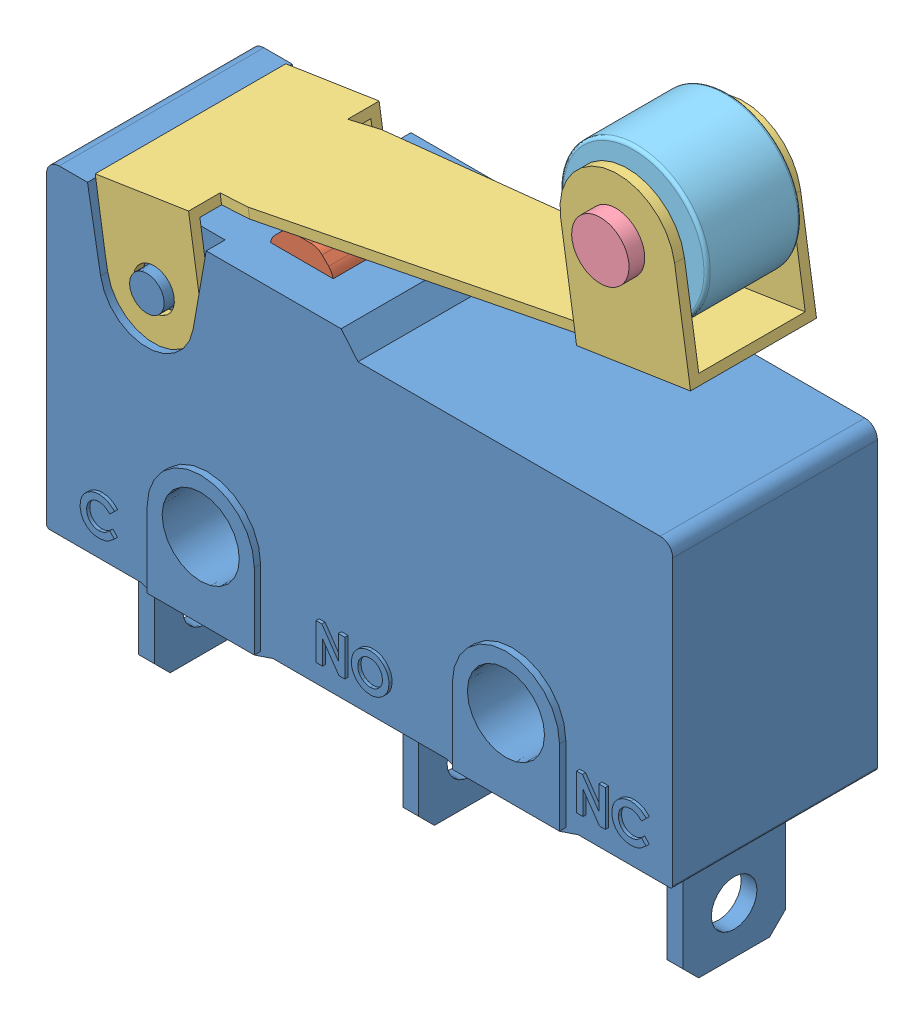
SolidWorks assembly Limit Switch, configuration Default. Lengths in mm.
Overall size (19.88 22.22 6.9).
5 component instances, 5 part files, 9 mates.
Components (placement in the parent):
- Body-1: Body [Default] at (-3.0926 15.7185 13.5391) size (19.88 14.3 6.9)
- Switch_Button-1: Switch_Button [Default] at (3.7604 12.3412 16.7891) size (2 4 4)
- Link-1: Link [Default] at (-1.7251 15.5431 16.7891) x (0.988221 0.153035 0) z (0 0 1) size (18.04 8.82 6.05)
- Wheel shaft-1: Wheel shaft [Default] at (13.789 21.2849 14.2391) x (-0.16928 0.985568 0) z (0 0 1) size (1.82 1.82 5.1)
- Wheel-1: Wheel [Default] at (13.789 21.2849 15.2941) x (0.999957 0.009288 0) z (0 0 1) size (4.67 4.67 2.99)
Mates (geometry in assembly coordinates):
- Coincident1: coincident anti-aligned: plane of Body-1 through (2.7604 13.7185 18.7891) normal (0 0 -1); plane of Switch_Button-1 through (2.7604 16.3412 18.7891) normal (0 0 1)
- Coincident2: coincident anti-aligned: plane of Body-1 through (4.7604 13.7185 14.7891) normal (-1 0 0); plane of Switch_Button-1 through (4.7604 16.3412 14.7891) normal (1 0 0)
- Concentric1: concentric aligned: cylinder of Body-1 through (0.0924 13.6084 19.4391) axis (0 0 1) radius 0.55; cylinder of Link-1 through (0.0924 13.6084 8.8141) axis (0 0 1) radius 0.65
- Tangent1: tangent anti-aligned: cylinder of Switch_Button-1 through (3.4675 15.8412 16.7891) axis (0 0 1) radius 0.5; plane of Link-1 through (-1.7251 15.5431 16.7891) normal (0.153035 -0.988221 0)
- Symmetric1: symmetric aligned: plane of Body-1 through (16.3874 14.6785 13.5391) normal (0 0 -1); plane of Link-1 through (16.3874 14.6785 20.0391) normal (0 0 1); plane of Body-1 through (-1.7251 15.5431 16.7891) normal (0 0 1)
- Concentric2: concentric aligned: cylinder of Link-1 through (13.789 21.2849 19.6091) axis (0 0 -1) radius 0.75; cylinder of Wheel shaft-1 through (13.789 21.2849 19.3391) axis (0 0 -1) radius 0.5
- Symmetric2: symmetric aligned: plane of Link-1 through (-1.7251 15.5431 16.7891) normal (0 0 1); plane of Wheel shaft-1 through (13.789 21.2849 19.3391) normal (0 0 1); plane of Wheel shaft-1 through (13.789 21.2849 14.2391) normal (0 0 -1)
- Concentric3: concentric aligned: cylinder of Wheel shaft-1 through (13.789 21.2849 19.3391) axis (0 0 -1) radius 0.5; cylinder of Wheel-1 through (13.789 21.2849 18.2841) axis (0 0 -1) radius 0.6
- Symmetric3: symmetric aligned: plane of Link-1 through (-1.7251 15.5431 16.7891) normal (0 0 1); plane of Wheel-1 through (13.789 21.2849 18.2841) normal (0 0 1); plane of Wheel-1 through (13.789 21.2849 15.2941) normal (0 0 -1)
